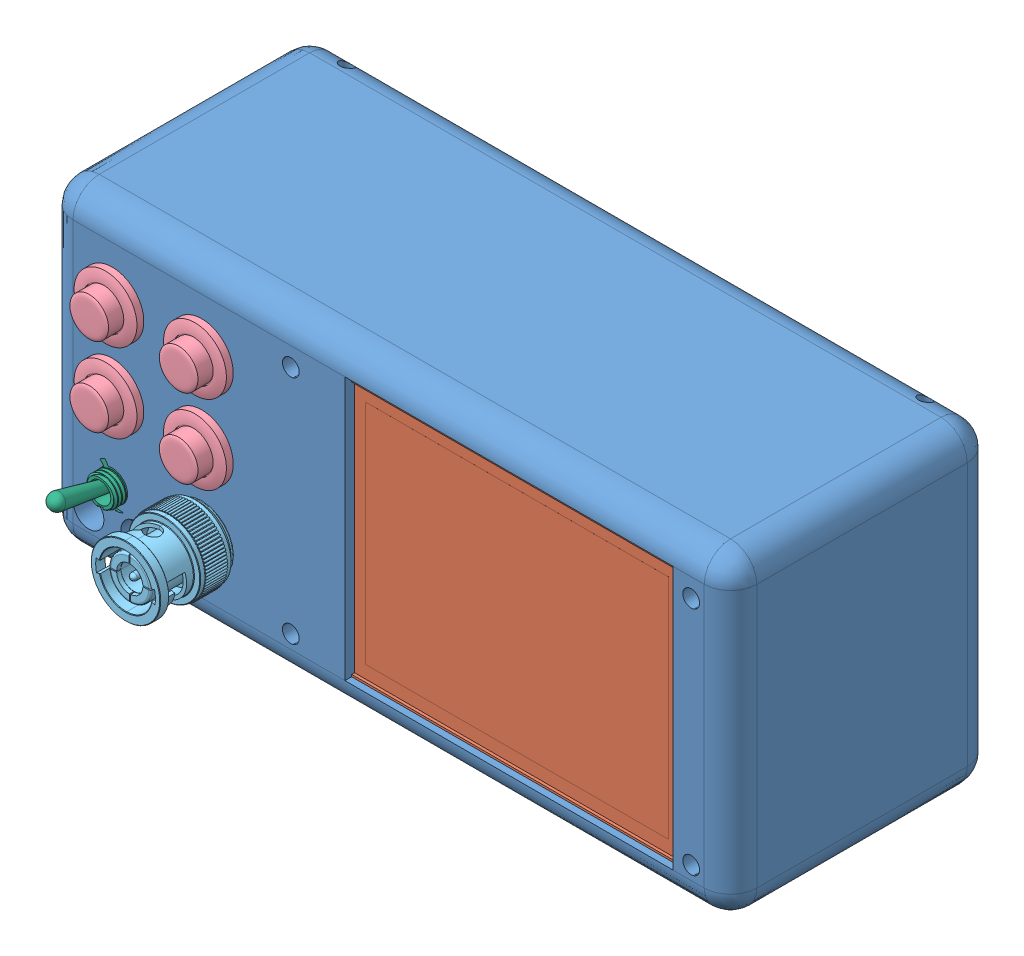
SolidWorks assembly Oscilloscope, configuration Default. Lengths in mm.
Overall size (130 60 64.5).
9 component instances, 6 part files, 20 mates.
Components (placement in the parent):
- Oscilloscope_Project-1: Oscilloscope_Project [Default] at (32.674 73.0262 131.8638) size (130 60 49.9)
- 2.8 TFT Module.stp-1: 2.8 TFT Module.stp [Default] at (53.8172 66.5329 126.2382) x (0 1 0) z (0 0 1) size (50.19 85.9 11.99)
- back-1: back [Default] at (30.9415 65.1359 87.8638) size (122 52 6)
- sw-1: sw [Default] at (-16.3359 82.0246 131.8638) x (0.466279 0.884638 0) z (0 0 1) size (11.94 11.94 27.46)
- sw-2: sw [Default] at (0.6641 82.0246 131.8638) x (0.466279 0.884638 0) z (0 0 1) size (11.94 11.94 27.46)
- sw-3: sw [Default] at (0.6641 67.0246 131.8638) x (0.466279 0.884638 0) z (0 0 1) size (11.94 11.94 27.46)
- sw-4: sw [Default] at (-16.3359 67.0246 131.8638) x (0.466279 0.884638 0) z (0 0 1) size (11.94 11.94 27.46)
- BNC Connector (Male).step-1: BNC Connector (Male).step [Default] at (0.6641 52.0246 132.5638) x (0.999716 0.023841 0) z (0 0 1) size (14.1 14.1 43.5)
- toggle-1: toggle [Default] at (-16.3359 52.0246 125.0638) size (12 14.45 32.81)
Mates (geometry in assembly coordinates):
- Concentric4: concentric aligned: cylinder of Oscilloscope_Project-1 through (17.5841 44.5746 127.8638) axis (0 0 1) radius 1.6; cylinder of 2.8 TFT Module.stp-1 through (17.5841 44.5746 28.3856) axis (0 0 1) radius 1.6129
- Coincident4: coincident anti-aligned: plane of Oscilloscope_Project-1 through (32.674 73.0262 127.8638) normal (0 0 -1); plane of 2.8 TFT Module.stp-1 through (53.8172 66.5329 127.8638) normal (0 0 1)
- Coincident6: coincident anti-aligned: plane of Oscilloscope_Project-1 through (97.1641 73.0262 81.8638) normal (-1 0 0); plane of back-1 through (97.1641 93.0246 81.8638) normal (1 0 0)
- Coincident7: coincident anti-aligned: plane of Oscilloscope_Project-1 through (32.674 93.0246 81.8638) normal (0 -1 0); plane of back-1 through (-24.8359 93.0246 81.8638) normal (0 1 0)
- Coincident8: coincident anti-aligned: plane of Oscilloscope_Project-1 through (97.1641 73.0262 81.8638) normal (-1 0 0); plane of back-1 through (97.1641 93.0246 81.8638) normal (1 0 0)
- Coincident9: coincident anti-aligned: plane of Oscilloscope_Project-1 through (32.674 93.0246 81.8638) normal (0 -1 0); plane of back-1 through (-24.8359 93.0246 81.8638) normal (0 1 0)
- Tangent1: tangent aligned: cylinder of Oscilloscope_Project-1 through (96.1641 73.0262 86.8638) axis (0 -1 0) radius 5; plane of back-1 through (30.9415 65.1359 81.8638) normal (0 0 -1)
- Concentric7: concentric anti-aligned: circle of Oscilloscope_Project-1; circle of sw-1
- Coincident10: coincident anti-aligned: plane of Oscilloscope_Project-1 through (32.674 73.0262 131.8638) normal (0 0 1); plane of sw-1 through (-16.3359 82.0246 131.8638) normal (0 0 -1)
- Concentric8: concentric anti-aligned: circle of Oscilloscope_Project-1; circle of sw-2
- Concentric9: concentric anti-aligned: circle of Oscilloscope_Project-1; circle of sw-3
- Concentric10: concentric anti-aligned: circle of Oscilloscope_Project-1; circle of sw-4
- Concentric11: concentric anti-aligned: circle of Oscilloscope_Project-1; circle of sw-4
- Coincident11: coincident anti-aligned: plane of Oscilloscope_Project-1 through (32.674 73.0262 131.8638) normal (0 0 1); plane of sw-2 through (0.6641 82.0246 131.8638) normal (0 0 -1)
- Coincident12: coincident anti-aligned: plane of Oscilloscope_Project-1 through (32.674 73.0262 131.8638) normal (0 0 1); plane of sw-4 through (-16.3359 67.0246 131.8638) normal (0 0 -1)
- Coincident13: coincident anti-aligned: plane of Oscilloscope_Project-1 through (32.674 73.0262 131.8638) normal (0 0 1); plane of sw-3 through (0.6641 67.0246 131.8638) normal (0 0 -1)
- Concentric12: concentric aligned: circle of Oscilloscope_Project-1; circle of BNC Connector (Male).step-1
- Coincident14: coincident aligned: plane of Oscilloscope_Project-1 through (32.674 73.0262 131.8638) normal (0 0 1); plane of BNC Connector (Male).step-1 through (0.5473 56.9233 131.8638) normal (0 0 1)
- Concentric13: concentric anti-aligned: circle of Oscilloscope_Project-1; circle of toggle-1
- Coincident15: coincident aligned: plane of Oscilloscope_Project-1 through (32.674 73.0262 131.8638) normal (0 0 1); plane of toggle-1 through (-16.3359 52.0246 131.8638) normal (0 0 1)
